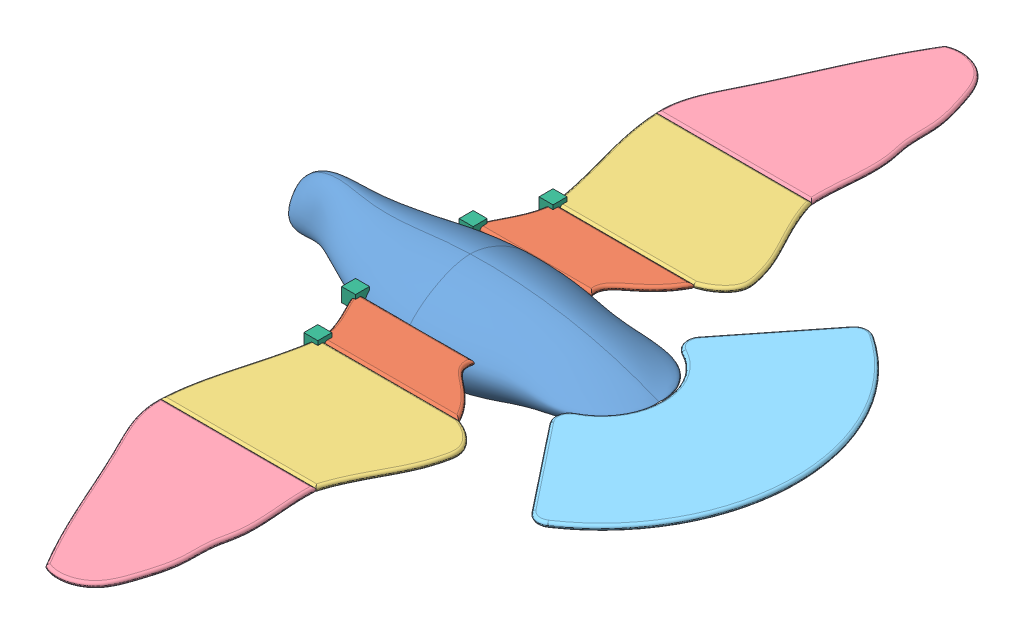
SolidWorks assembly pigeon_assembly, configuration Default. Lengths in mm.
Overall size (355.83 69.51 657.25).
16 component instances, 6 part files, 31 mates.
Components (placement in the parent):
- torso_contours-1: torso_contours [Default] at (321.9795 -52 0) x (0 0 -1) z (1 0 0) size (94.74 69.51 256.9)
- upper_wing-1: upper_wing [Default] at (217.3123 -2 322.6835) x (0 0 -1) z (1 0 0) size (42 8.51 121.5)
- mid_wing-1: mid_wing [Default] at (217.3123 -2 322.6835) x (0 0 -1) z (1 0 0) size (102.24 9.28 147.46)
- hand_wing-1: hand_wing [Default] at (217.3123 -2 322.6835) x (0 0 -1) z (1 0 0) size (157.2 28.03 132.9)
- tail-1: tail [Default] at (323.7845 -54 0) x (0 0 -1) z (1 0 0) size (235.93 4 125.9)
- upper_wing-3: upper_wing [Default] at (217.3123 2 -322.6835) x (0 0 1) z (1 0 0) size (42 8.51 121.5)
- mid_wing-3: mid_wing [Default] at (217.3123 2 -322.6835) x (0 0 1) z (1 0 0) size (102.24 9.28 147.46)
- hand_wing-3: hand_wing [Default] at (217.3123 2 -322.6835) x (0 0 1) z (1 0 0) size (157.2 28.03 132.9)
- ghost_component-1: ghost_component [Default] at (102.0339 -5 88.9981) x (0 0 -1) z (1 0 0) size (10 10 10)
- ghost_component-2: ghost_component [Default] at (86.9795 -5 47) x (0 0 -1) z (1 0 0) size (10 10 10)
- ghost_component-3: ghost_component [Default] at (102.0339 -5 88.9981) x (0 0 -1) z (1 0 0) size (10 10 10)
- ghost_component-4: ghost_component [Default] at (86.9795 -5 -37) x (0 0 -1) z (1 0 0) size (10 10 10)
- ghost_component-5: ghost_component [Default] at (86.9795 -5 -37) x (0 0 -1) z (1 0 0) size (10 10 10)
- ghost_component-6: ghost_component [Default] at (86.9795 -5 47) x (0 0 -1) z (1 0 0) size (10 10 10)
- ghost_component-7: ghost_component [Default] at (102.0339 -5 -78.9981) x (0 0 -1) z (1 0 0) size (10 10 10)
- ghost_component-8: ghost_component [Default] at (102.0339 -5 -78.9981) x (0 0 -1) z (1 0 0) size (10 10 10)
Mates (geometry in assembly coordinates):
- Coincident19: coincident aligned: line of torso_contours-1 through (229.9795 0 52.1057) axis (0 0 -1); line of tail-1 through (229.9795 0 44.8451) axis (0 0 -1)
- Coincident22: coincident aligned: plane of torso_contours-1 through (256.6828 0 0) normal (0 0 -1); plane of tail-1 through (258.4878 0 0) normal (0 0 -1)
- Coincident76: coincident aligned: line of mid_wing-1 through (188.6353 0 176.9607) axis (-1 0 0); line of hand_wing-1 through (188.6353 0 176.9607) axis (-1 0 0)
- Coincident77: coincident: point of mid_wing-1; point of hand_wing-1
- Coincident78: coincident aligned: line of mid_wing-3 through (188.6353 0 -176.9607) axis (-1 0 0); line of hand_wing-3 through (188.6353 0 -176.9607) axis (-1 0 0)
- Coincident79: coincident: point of mid_wing-3; point of hand_wing-3
- Coincident80: coincident anti-aligned: line of mid_wing-1 through (97.0339 0 83.9981) axis (0 1 0); line of ? through (97.0339 5.5 83.9981) axis (0 -1 0)
- Coincident81: coincident: line of mid_wing-1 through (197.7314 0 83.9981) axis (-1 0 0); plane of ?
- Coincident82: coincident aligned: line of upper_wing-1 through (197.7314 0 83.9981) axis (-1 0 0); line of ? through (102.5339 0 83.9981) axis (-1 0 0)
- Coincident83: coincident: point of upper_wing-1; plane of ? through (97.0339 -5 88.9981) normal (1 0 0)
- Coincident84: coincident anti-aligned: line of upper_wing-1 through (166.7932 0 42) axis (-1 0 0); plane of ?
- Coincident85: coincident anti-aligned: line of upper_wing-1 through (81.9795 0 42) axis (0 1 0); line of ? through (81.9795 5.5 42) axis (0 -1 0)
- Coincident86: coincident aligned: line of torso_contours-1 through (269.5633 0 42) axis (-1 0 0); line of ? through (87.4795 0 42) axis (-1 0 0)
- Coincident87: coincident aligned: plane of torso_contours-1 through (81.9795 -52 0) normal (1 0 0); plane of ? through (81.9795 -5 47) normal (1 0 0)
- Coincident88: coincident aligned: line of ? through (97.0339 0 78.4981) axis (0 0 1); line of ? through (97.0339 0 78.4981) axis (0 0 1)
- Coincident89: coincident aligned: plane of ? through (102.0339 5 78.9981) normal (0 0 -1); plane of ? through (102.0339 5 78.9981) normal (0 0 -1)
- Coincident90: coincident aligned: line of ? through (81.9795 0 36.5) axis (0 0 1); line of ? through (81.9795 0 36.5) axis (0 0 1)
- Coincident91: coincident aligned: plane of ? through (86.9795 5 37) normal (0 0 -1); plane of ? through (86.9795 5 37) normal (0 0 -1)
- Coincident93: coincident aligned: line of torso_contours-1 through (269.5633 0 -42) axis (-1 0 0); line of ? through (87.4795 0 -42) axis (-1 0 0)
- Coincident94: coincident aligned: plane of torso_contours-1 through (81.9795 -52 0) normal (1 0 0); plane of ? through (81.9795 -5 -37) normal (1 0 0)
- Coincident97: coincident aligned: line of upper_wing-3 through (197.7314 0 -83.9981) axis (-1 0 0); line of ? through (102.5339 0 -83.9981) axis (-1 0 0)
- Coincident98: coincident: point of upper_wing-3; plane of ? through (97.0339 -5 -78.9981) normal (1 0 0)
- Coincident99: coincident aligned: line of mid_wing-3 through (97.0339 0 -83.9981) axis (0 -1 0); line of ? through (97.0339 5.5 -83.9981) axis (0 -1 0)
- Coincident100: coincident: line of mid_wing-3 through (197.7314 0 -83.9981) axis (-1 0 0); plane of ?
- Coincident101: coincident aligned: line of upper_wing-3 through (81.9795 0 -42) axis (0 -1 0); line of ghost_component-4 through (81.9795 5.5 -42) axis (0 -1 0)
- Coincident102: coincident: line of upper_wing-3 through (166.7932 0 -42) axis (-1 0 0); plane of ghost_component-4
- Coincident104: coincident aligned: line of ? through (81.9795 0 -47.5) axis (0 0 1); line of ghost_component-4 through (81.9795 0 -47.5) axis (0 0 1)
- Coincident105: coincident aligned: plane of ? through (86.9795 5 -47) normal (0 0 -1); plane of ghost_component-4 through (86.9795 5 -47) normal (0 0 -1)
- Coincident106: coincident aligned: line of ? through (97.0339 0 -89.4981) axis (0 0 1); line of ? through (97.0339 0 -89.4981) axis (0 0 1)
- Coincident107: coincident aligned: plane of ? through (102.0339 5 -88.9981) normal (0 0 -1); plane of ? through (102.0339 5 -88.9981) normal (0 0 -1)
- Coincident108: coincident: unknown of ?
